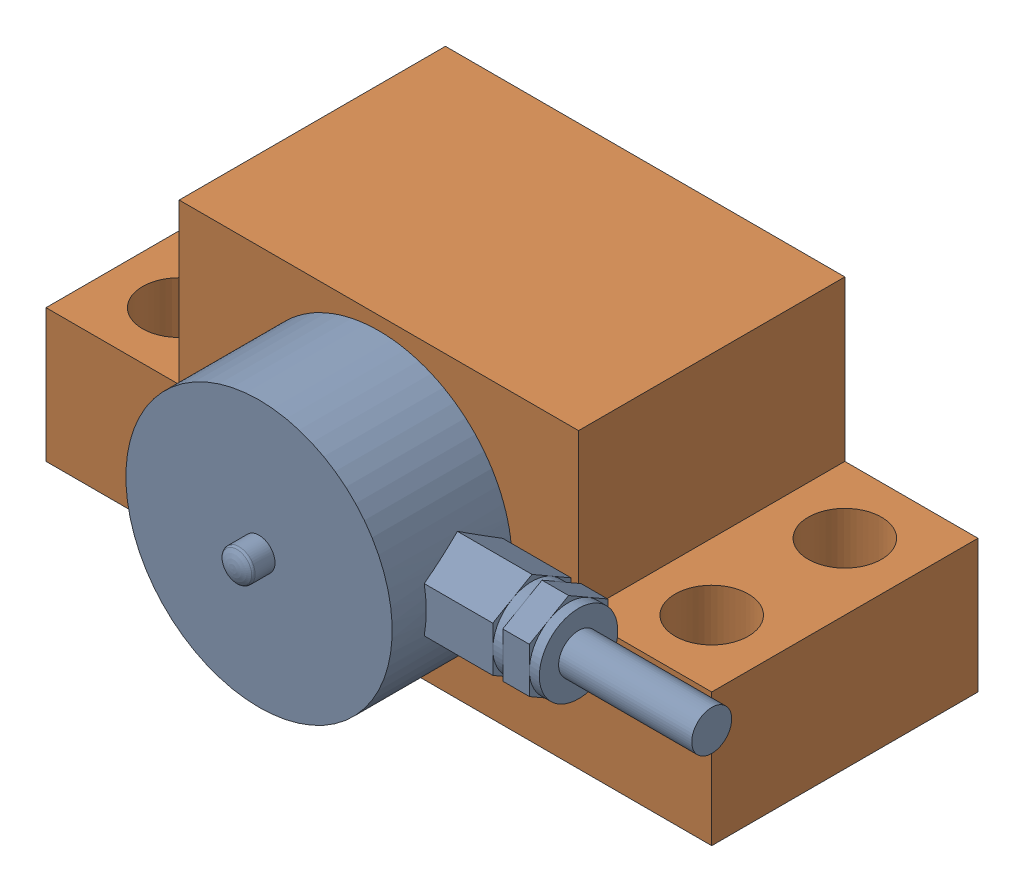
SolidWorks assembly loadcel yatay montaj-2, configuration Default. Lengths in mm.
Overall size (53.5 22 31).
2 component instances, 2 part files, 0 mates.
Components (placement in the parent):
- Mini_Loadcell-1: Mini_Loadcell [Default] at (0 11 19) x (-1 0 0) z (0 1 0) size (38.5 12 20)
- Loadcell yatay ayak-1: Loadcell yatay ayak [Default] at origin size (50 22 20)
